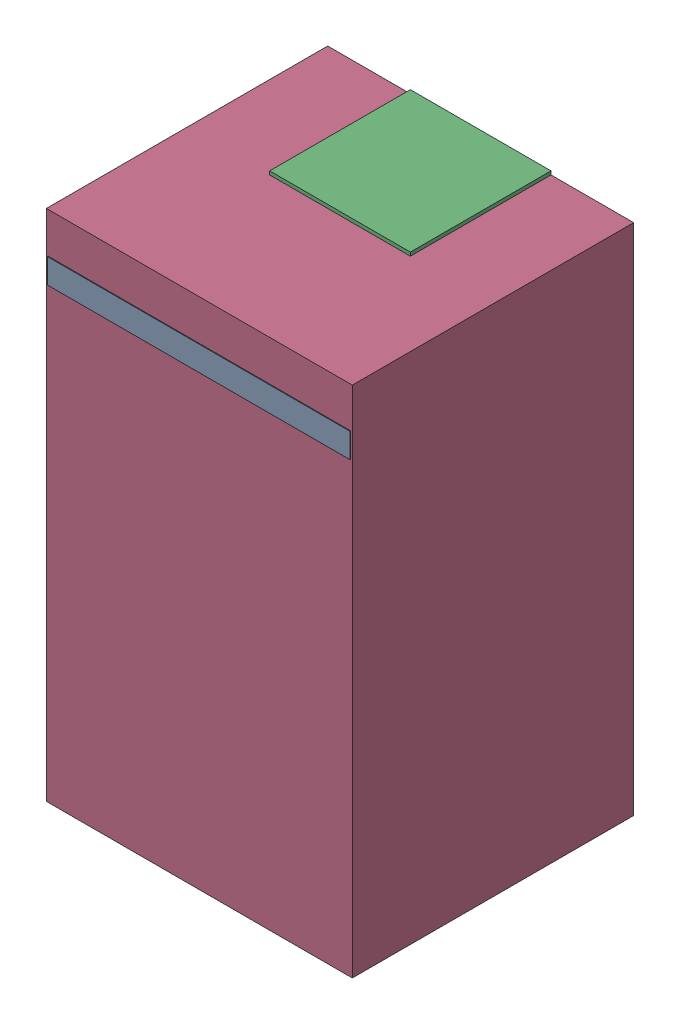
SolidWorks assembly C40, configuration Default. Lengths in mm.
Overall size (4.35 7.4 4.01).
8 component instances, 3 part files, 0 mates.
Components (placement in the parent):
- 870941440-1: 870941440 [Default] at (68.4522 37.8735 0) size (4.3 0.35 4.01)
  - Extruded_36-1: Extruded_36 [Default] at origin size (4.3 0.35 4.01)
- 870941600-1: 870941600 [Default] at (68.4522 31.3736 0) size (2 0.2 2)
  - Extruded_37-1: Extruded_37 [Default] at origin size (2 0.2 2)
- 870941600-2: 870941600 [Default] at (68.4522 38.5736 0) size (2 0.2 2)
  - Extruded_37-1: Extruded_37 [Default] at origin size (2 0.2 2)
- 870941760-1: 870941760 [Default] at (68.4523 34.9735 0) size (4.35 7.3 4)
  - Extruded_38-1: Extruded_38 [Default] at origin size (4.35 7.3 4)
